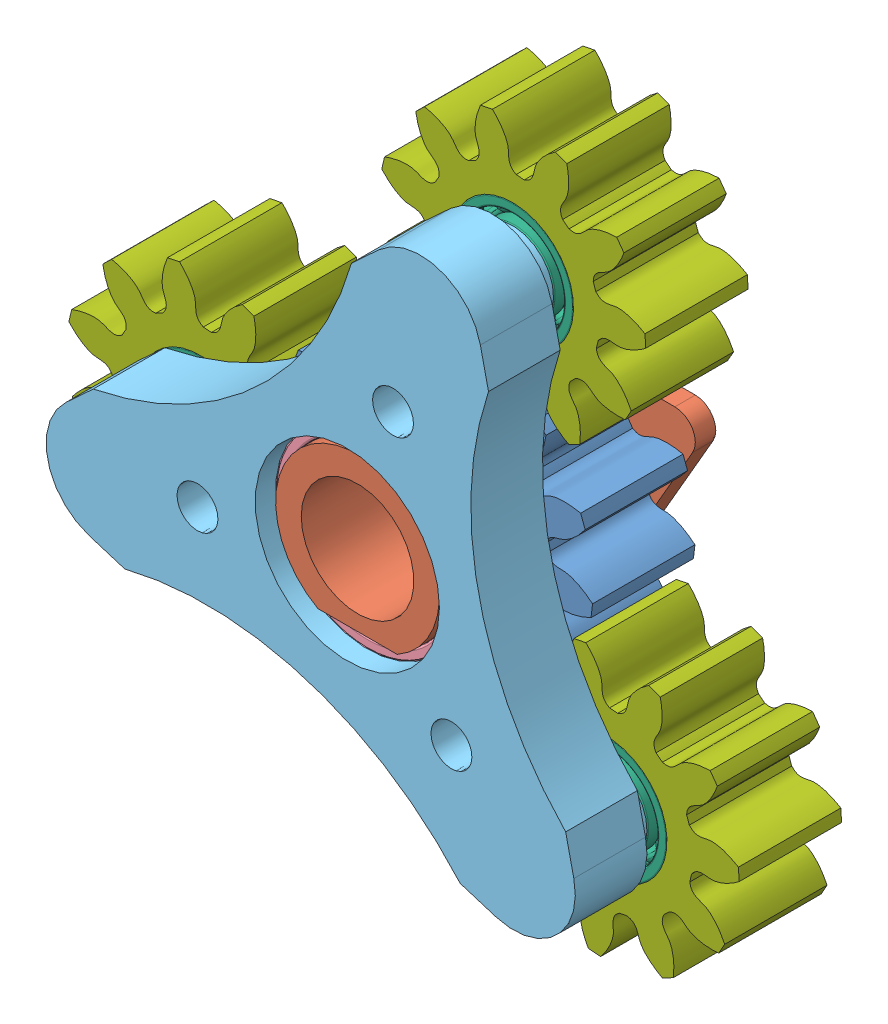
SolidWorks assembly Reducer_PlanetGearChains2, configuration Default. Lengths in mm.
Overall size (36.76 35.68 12.5).
11 component instances, 7 part files, 24 mates.
Components (placement in the parent):
- Reducer_PGT_SunGear2-1: Reducer_PGT_SunGear2 [默认] at origin size (14.95 14.85 5)
- Reducer_PGT_Joint2-1: Reducer_PGT_Joint2 [默认] at (0 0 -3) x (-1 0 0) z (0 0 1) size (14.99 13.25 12)
- Reducer_PGT_Joint3-1: Reducer_PGT_Joint3 [默认] at (0 0 4) x (0.999186 0.040349 0) z (0 0 1) size (10 10 2)
- GB╱T 276-2013[617╱8-2Z]-1: GB╱T 276-2013[617╱8-2Z] [617╱8-2Z] at (0 0 7.25) x (0 0 -1) z (0.993401 0.114691 0) size (2.5 12 12)
- Reducer_PGT_PlanetCarrier-1: Reducer_PGT_PlanetCarrier [默认] at (0 0 8.5) x (-0.954684 0.297621 0) z (0 0 -1) size (26.78 24 8.5)
- GB╱T 276-2013[617╱3]-1: GB╱T 276-2013[617╱3] [617╱3] at (8.1356 -8.8211 4) x (0 0 1) z (0.491925 0.870638 0) size (2 6 6)
- GB╱T 276-2013[617╱3]-2: GB╱T 276-2013[617╱3] [617╱3] at (-11.7071 -2.6351 4) x (0 0 1) z (-1 0 0) size (2 6 6)
- GB╱T 276-2013[617╱3]-3: GB╱T 276-2013[617╱3] [617╱3] at (3.5715 11.4562 4) x (0 0 1) z (-0.14803 -0.988983 0) size (2 6 6)
- Reducer_PGT_PlanetGear-1: Reducer_PGT_PlanetGear [默认] at (-11.7071 -2.6351 0) x (-0.22802 -0.973657 0) z (0 0 1) size (12.94 12.81 5)
- Reducer_PGT_PlanetGear-2: Reducer_PGT_PlanetGear [默认] at (3.5715 11.4562 0) x (0.885422 0.464788 0) z (0 0 1) size (12.94 12.81 5)
- Reducer_PGT_PlanetGear-3: Reducer_PGT_PlanetGear [默认] at (8.1356 -8.8211 0) x (-0.055296 0.99847 0) z (0 0 1) size (12.94 12.81 5)
Mates (geometry in assembly coordinates):
- 同心1: concentric anti-aligned: cylinder of Reducer_PGT_SunGear2-1 through (0 0 -5) axis (0 0 1) radius 4; cylinder of Reducer_PGT_Joint2-1 through (0 0 9) axis (0 0 -1) radius 4
- 重合1: coincident anti-aligned: plane of Reducer_PGT_SunGear2-1 through (0 0 0) normal (0 0 -1); plane of Reducer_PGT_Joint2-1 through (4.7086 5.8377 0) normal (0 0 1)
- 同心2: concentric aligned: cylinder of Reducer_PGT_Joint2-1 through (0 0 9) axis (0 0 -1) radius 4; cylinder of Reducer_PGT_Joint3-1 through (0 0 6) axis (0 0 -1) radius 4
- 重合3: coincident anti-aligned: plane of Reducer_PGT_SunGear2-1 through (0 0 5) normal (0 0 1); plane of Reducer_PGT_Joint3-1 through (0 0 5) normal (0 0 -1)
- 同心3: concentric anti-aligned: cylinder of Reducer_PGT_Joint2-1 through (0 0 9) axis (0 0 -1) radius 4; cylinder of GB╱T 276-2013[617╱8-2Z]-1 through (0 0 10.75) axis (0 0 1) radius 4
- 重合4: coincident anti-aligned: plane of Reducer_PGT_Joint3-1 through (0 0 6) normal (0 0 1); plane of GB╱T 276-2013[617╱8-2Z]-1 through (-0.5097 4.4151 6) normal (0 0 -1)
- 同心4: concentric aligned: cylinder of GB╱T 276-2013[617╱8-2Z]-1 through (0 0 10.75) axis (0 0 1) radius 6; cylinder of Reducer_PGT_PlanetCarrier-1 through (0 0 -1.5) axis (0 0 1) radius 5.975
- 重合5: coincident anti-aligned: plane of GB╱T 276-2013[617╱8-2Z]-1 through (-0.6767 5.8611 8.5) normal (0 0 1); plane of Reducer_PGT_PlanetCarrier-1 through (-11.7071 -2.6351 8.5) normal (0 0 -1)
- 同心5: concentric anti-aligned: cylinder of Reducer_PGT_PlanetCarrier-1 through (8.1356 -8.8211 1) axis (0 0 1) radius 1.525; cylinder of GB╱T 276-2013[617╱3]-1 through (8.1356 -8.8211 0.5) axis (0 0 -1) radius 1.5
- 重合6: coincident anti-aligned: plane of Reducer_PGT_PlanetCarrier-1 through (8.1356 -8.8211 5) normal (0 0 -1); plane of GB╱T 276-2013[617╱3]-1 through (9.8073 -9.7656 5) normal (0 0 1)
- 同心6: concentric anti-aligned: cylinder of Reducer_PGT_PlanetCarrier-1 through (-11.7071 -2.6351 1) axis (0 0 1) radius 1.525; cylinder of GB╱T 276-2013[617╱3]-2 through (-11.7071 -2.6351 0.5) axis (0 0 -1) radius 1.5
- 同心7: concentric anti-aligned: cylinder of Reducer_PGT_PlanetCarrier-1 through (3.5715 11.4562 1) axis (0 0 1) radius 1.525; cylinder of GB╱T 276-2013[617╱3]-3 through (3.5715 11.4562 0.5) axis (0 0 -1) radius 1.5
- 重合7: coincident anti-aligned: plane of Reducer_PGT_PlanetCarrier-1 through (-11.7071 -2.6351 5) normal (0 0 -1); plane of GB╱T 276-2013[617╱3]-2 through (-11.7071 -0.7151 5) normal (0 0 1)
- 重合8: coincident anti-aligned: plane of Reducer_PGT_PlanetCarrier-1 through (3.5715 11.4562 5) normal (0 0 -1); plane of GB╱T 276-2013[617╱3]-3 through (1.6726 11.7404 5) normal (0 0 1)
- 同心8: concentric anti-aligned: cylinder of GB╱T 276-2013[617╱3]-2 through (-11.7071 -2.6351 0.5) axis (0 0 -1) radius 3; cylinder of Reducer_PGT_PlanetGear-1 through (-11.7071 -2.6351 -5) axis (0 0 1) radius 2.975
- 同心9: concentric anti-aligned: cylinder of GB╱T 276-2013[617╱3]-1 through (8.1356 -8.8211 0.5) axis (0 0 -1) radius 3; cylinder of Reducer_PGT_PlanetGear-3 through (8.1356 -8.8211 -5) axis (0 0 1) radius 2.975
- 同心10: concentric anti-aligned: cylinder of GB╱T 276-2013[617╱3]-3 through (3.5715 11.4562 0.5) axis (0 0 -1) radius 3; cylinder of Reducer_PGT_PlanetGear-2 through (3.5715 11.4562 -5) axis (0 0 1) radius 2.975
- 重合9: coincident aligned: plane of Reducer_PGT_SunGear2-1 through (0 0 0) normal (0 0 -1); plane of Reducer_PGT_PlanetGear-1 through (-11.7071 -2.6351 0) normal (0 0 -1)
- 重合10: coincident aligned: plane of Reducer_PGT_SunGear2-1 through (0 0 0) normal (0 0 -1); plane of Reducer_PGT_PlanetGear-2 through (3.5715 11.4562 0) normal (0 0 -1)
- 重合11: coincident aligned: plane of Reducer_PGT_SunGear2-1 through (0 0 0) normal (0 0 -1); plane of Reducer_PGT_PlanetGear-3 through (8.1356 -8.8211 0) normal (0 0 -1)
- 齿轮配合1: gear = 13 : 11 mm: circle of Reducer_PGT_PlanetGear-1; circle of Reducer_PGT_SunGear2-1
- 齿轮配合2: gear = 11 : 13 mm: circle of Reducer_PGT_SunGear2-1; circle of Reducer_PGT_PlanetGear-2
- 齿轮配合3: gear = 13 : 11 mm: circle of Reducer_PGT_PlanetGear-3; circle of Reducer_PGT_SunGear2-1
- 重合12: coincident anti-aligned: plane of Reducer_PGT_SunGear2-1 through (-1.9365 -3.5 -5) normal (0 1 0); plane of Reducer_PGT_Joint2-1 through (1.9365 -3.5 9) normal (0 -1 0)
